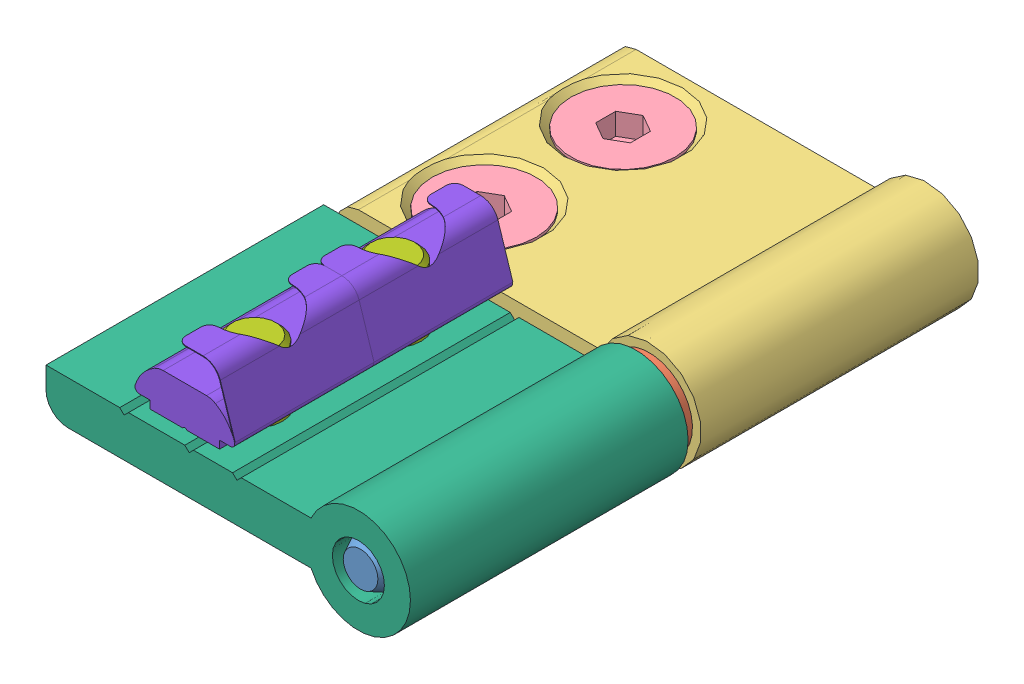
SolidWorks assembly 21.1377 HINGE L 30_45 RIGHT HAND, configuration Default. Lengths in mm.
Overall size (42.08 26.47 65.5).
12 component instances, 8 part files, 24 mates.
Components (placement in the parent):
- 21.1922_2 HINGE PIN 6.15x65-1: 21.1922_2 HINGE PIN 6.15x65 [Default] at origin size (6.07 6.07 65)
- 21.1971 HINGE WASHER-1: 21.1971 HINGE WASHER [Default] at (0 0 31.75) x (0.969126 0.246564 0) z (0 0 1) size (10 10 1.5)
- 21.1378_1 HINGE L 45 AL BLOCK-1: 21.1378_1 HINGE L 45 AL BLOCK [Default] at (0 0 15.75) x (-1 0 0) z (0 0 -1) size (42 12 32)
- 21.1506 M6x16 C'SUNK-1: 21.1506 M6x16 C'SUNK [Default] at (-27 2 23.75) x (1 0 0) z (0 1 0) size (12 12 16)
- 21.1506 M6x16 C'SUNK-2: 21.1506 M6x16 C'SUNK [Default] at (-27 2 7.75) x (1 0 0) z (0 1 0) size (12 12 16)
- 21.1330 M6 SQUARE NUT-1: 21.1330 M6 SQUARE NUT [Default] at (-27 -7 23.75) x (1 0 0) z (0 1 0) size (13 13 5.5)
- 21.1330 M6 SQUARE NUT-2: 21.1330 M6 SQUARE NUT [Default] at (-27 -7 7.75) x (1 0 0) z (0 1 0) size (13 13 5.5)
- 21.1376_1 HINGE 30 L AL BLOCK-1: 21.1376_1 HINGE 30 L AL BLOCK [Default] at (0 0 49.25) x (-1 0 0) z (0 0 1) size (42 12 32)
- 21.1518 M6X12 CSUNK-1: 21.1518 M6X12 CSUNK [Default] at (-20 -2.5 57.25) x (0.907596 0 0.419844) z (0 -1 0) size (12 12 12)
- 21.1518 M6X12 CSUNK-2: 21.1518 M6X12 CSUNK [Default] at (-20 -2.5 41.25) x (0.965656 0 0.259823) z (0 -1 0) size (12 12 12)
- 21.1569 M6 SQUARE NUT 30 POS FXG-1: 21.1569 M6 SQUARE NUT 30 POS FXG [Default] at (-20 4.1 57.25) x (-1 0 0) z (0 0 1) size (11.55 8.37 16)
- 21.1569 M6 SQUARE NUT 30 POS FXG-2: 21.1569 M6 SQUARE NUT 30 POS FXG [Default] at (-20 4.1 41.25) x (-1 0 0) z (0 0 1) size (11.55 8.37 16)
Mates (geometry in assembly coordinates):
- Coincident1: coincident aligned: axis of 21.1922_2 HINGE PIN 6.15x65-1; axis of 21.1971 HINGE WASHER-1
- Coincident2: coincident aligned: axis of 21.1378_1 HINGE L 45 AL BLOCK-1; axis of 21.1922_2 HINGE PIN 6.15x65-1
- Distance1: distance = 0.25 mm aligned: plane of 21.1922_2 HINGE PIN 6.15x65-1 through (0 0 0) normal (0 0 -1); plane of 21.1378_1 HINGE L 45 AL BLOCK-1 through (-14.3887 -0.0537 -0.25) normal (0 0 -1)
- Coincident5: coincident anti-aligned: plane of 21.1971 HINGE WASHER-1 through (0 0 31.75) normal (0 0 -1); plane of 21.1378_1 HINGE L 45 AL BLOCK-1 through (-14.3887 -0.0537 31.75) normal (0 0 1)
- Coincident7: coincident aligned: axis of 21.1506 M6x16 C'SUNK-2; axis of 21.1378_1 HINGE L 45 AL BLOCK-1
- Coincident8: coincident aligned: axis of 21.1506 M6x16 C'SUNK-1; axis of 21.1378_1 HINGE L 45 AL BLOCK-1
- Coincident11: coincident aligned: plane of 21.1506 M6x16 C'SUNK-1 through (-24 2 23.75) normal (0 1 0); plane of 21.1506 M6x16 C'SUNK-2 through (-24 2 7.75) normal (0 1 0)
- Distance2: distance = 0.5 mm aligned: plane of 21.1506 M6x16 C'SUNK-2 through (-24 2 7.75) normal (0 1 0); plane of 21.1378_1 HINGE L 45 AL BLOCK-1 through (-33.5 2.5 15.75) normal (0 1 0)
- Coincident19: coincident aligned: axis of 21.1330 M6 SQUARE NUT-2; axis of 21.1506 M6x16 C'SUNK-2
- Coincident20: coincident aligned: axis of 21.1506 M6x16 C'SUNK-1; axis of 21.1330 M6 SQUARE NUT-1
- Distance5: distance = 4.5 mm anti-aligned: plane of 21.1330 M6 SQUARE NUT-2 through (-27 -7 7.75) normal (0 1 0); plane of 21.1378_1 HINGE L 45 AL BLOCK-1 through (-27.5 -2.5 15.75) normal (0 -1 0)
- Coincident22: coincident aligned: plane of 21.1330 M6 SQUARE NUT-1 through (-27 -7 23.75) normal (0 1 0); plane of 21.1330 M6 SQUARE NUT-2 through (-27 -7 7.75) normal (0 1 0)
- Coincident23: coincident anti-aligned: axis of 21.1922_2 HINGE PIN 6.15x65-1; axis of 21.1376_1 HINGE 30 L AL BLOCK-1
- Coincident24: coincident anti-aligned: plane of 21.1971 HINGE WASHER-1 through (0 0 33.25) normal (0 0 1); plane of 21.1376_1 HINGE 30 L AL BLOCK-1 through (-14.3887 0.0537 33.25) normal (0 0 -1)
- Coincident25: coincident aligned: axis of 21.1518 M6X12 CSUNK-1; axis of 21.1376_1 HINGE 30 L AL BLOCK-1
- Coincident26: coincident aligned: axis of 21.1518 M6X12 CSUNK-2; axis of 21.1376_1 HINGE 30 L AL BLOCK-1
- Coincident27: coincident aligned: plane of 21.1376_1 HINGE 30 L AL BLOCK-1 through (-33.5 -2.5 49.25) normal (0 -1 0); plane of 21.1518 M6X12 CSUNK-1 through (-17.2772 -2.5 58.5095) normal (0 -1 0)
- Coincident28: coincident aligned: plane of 21.1376_1 HINGE 30 L AL BLOCK-1 through (-33.5 -2.5 49.25) normal (0 -1 0); plane of 21.1518 M6X12 CSUNK-2 through (-17.103 -2.5 42.0295) normal (0 -1 0)
- Coincident29: coincident anti-aligned: axis of 21.1569 M6 SQUARE NUT 30 POS FXG-1; axis of 21.1518 M6X12 CSUNK-1
- Coincident30: coincident anti-aligned: axis of 21.1518 M6X12 CSUNK-2; axis of 21.1569 M6 SQUARE NUT 30 POS FXG-2
- Distance6: distance = 2.5 mm anti-aligned: plane of 21.1569 M6 SQUARE NUT 30 POS FXG-1 through (-14.75 5 57.25) normal (0 -1 0); plane of 21.1376_1 HINGE 30 L AL BLOCK-1 through (-5.4544 2.5 49.25) normal (0 1 0)
- Distance7: distance = 2.5 mm anti-aligned: plane of 21.1376_1 HINGE 30 L AL BLOCK-1 through (-5.4544 2.5 49.25) normal (0 1 0); plane of 21.1569 M6 SQUARE NUT 30 POS FXG-2 through (-14.75 5 41.25) normal (0 -1 0)
- Angle1: planar angle = 0 rad aligned: plane of 21.1569 M6 SQUARE NUT 30 POS FXG-1 through (-20 6.2007 65.25) normal (0 0 1); plane of 21.1376_1 HINGE 30 L AL BLOCK-1 through (-14.3887 0.0537 65.25) normal (0 0 1)
- Angle2: planar angle = 0 rad aligned: plane of 21.1569 M6 SQUARE NUT 30 POS FXG-2 through (-20 6.2007 49.25) normal (0 0 1); plane of 21.1376_1 HINGE 30 L AL BLOCK-1 through (-14.3887 0.0537 65.25) normal (0 0 1)
